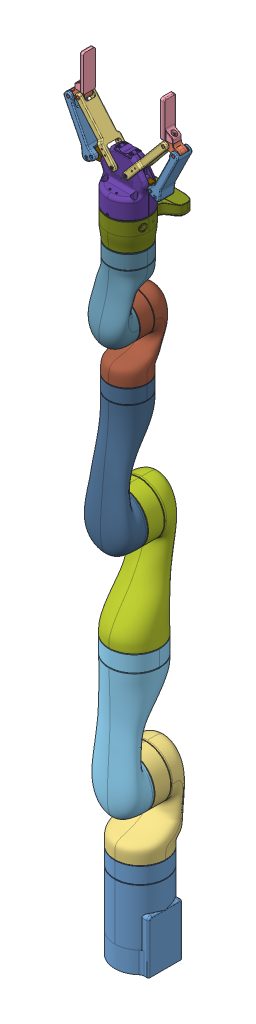
SolidWorks assembly KinovaGen3_7dof, configuration Default. Lengths in mm.
Overall size (315.52 1396.9 175).
44 component instances, 22 part files, 24 mates.
Components (placement in the parent):
- Link0.step-1: Link0.step [Default] at (18.2883 -95.8789 -1.2988) size (92.5 170.85 92.16)
- Link1.STEP-1: Link1.STEP [Default] at (23.0425 151.8211 81.9747) x (0 1 0) z (-0.992416 0 0.122925) size (174.42 105.54 103.77)
  - KR10643^GEN3 SIMPLIFIED Shoulder_Kinova Gen3 Modular Robotic Arm(2)_Kinova Gen3 Modular Robotic Arm.STEP-1: KR10643^GEN3 SIMPLIFIED Shoulder_Kinova Gen3 Modular Robotic Arm(2)_Kinova Gen3 Modular Robotic Arm.STEP [Default] at (34.35 77.8922 -4.8576) x (1 0 0) z (0 0.122925 0.992416) size (80 30.1 80)
  - GEN3 SIMPLIFIED SHOULDER_1^GEN3 SIMPLIFIED Shoulder_Kinova Gen3 Modular Robotic Arm(2)_Kinova Gen3 Modular Robotic Arm.STEP-1: GEN3 SIMPLIFIED SHOULDER_1^GEN3 SIMPLIFIED Shoulder_Kinova Gen3 Modular Robotic Arm(2)_Kinova Gen3 Modular Robotic Arm.STEP [Default] at (-91.65 83.2264 -5.5183) x (1 0 0) z (0 0.122925 0.992416) size (172.05 94.85 92.82)
  - KR10643^GEN3 SIMPLIFIED Shoulder_Kinova Gen3 Modular Robotic Arm(2)_Kinova Gen3 Modular Robotic Arm.STEP-2: KR10643^GEN3 SIMPLIFIED Shoulder_Kinova Gen3 Modular Robotic Arm(2)_Kinova Gen3 Modular Robotic Arm.STEP [Default] at (-94.025 83.2264 -5.5183) x (0 0.992416 -0.122925) z (0 -0.122925 -0.992416) size (80 30.1 80)
- LInk2.STEP-1: LInk2.STEP [Default] at (-176.0617 181.4169 81.0247) x (0.642788 0.760235 0.094166) z (0.766044 -0.637913 -0.079015) size (274.25 129.5 251.02)
  - KR10643_1^GEN3 SIMPLIFIED HalfArm1_Kinova Gen3 Modular Robotic Arm(2)_Kinova Gen3 Modular Robotic Arm.STEP-1: KR10643_1^GEN3 SIMPLIFIED HalfArm1_Kinova Gen3 Modular Robotic Arm(2)_Kinova Gen3 Modular Robotic Arm.STEP [Default] at (281.7393 -97.4259 17.2986) x (0.094166 0.992416 -0.079015) z (0.642788 0 0.766044) size (80 30.1 80)
  - GEN3 SIMPLIFIED HALF ARM 1^GEN3 SIMPLIFIED HalfArm1_Kinova Gen3 Modular Robotic Arm(2)_Kinova Gen3 Modular Robotic Arm.STEP-1: GEN3 SIMPLIFIED HALF ARM 1^GEN3 SIMPLIFIED HalfArm1_Kinova Gen3 Modular Robotic Arm(2)_Kinova Gen3 Modular Robotic Arm.STEP [Default] at (121.805 -71.5655 151.4994) x (0.760235 -0.122925 -0.637913) z (0.642788 0 0.766044) size (270.81 96.95 92.17)
  - KR10643_1^GEN3 SIMPLIFIED HalfArm1_Kinova Gen3 Modular Robotic Arm(2)_Kinova Gen3 Modular Robotic Arm.STEP-2: KR10643_1^GEN3 SIMPLIFIED HalfArm1_Kinova Gen3 Modular Robotic Arm(2)_Kinova Gen3 Modular Robotic Arm.STEP [Default] at (121.2047 -77.8922 152.0032) x (0.760235 -0.122925 -0.637913) z (0.642788 0 0.766044) size (80 30.1 80)
- Link3.STEP-1: Link3.STEP [Default] at (-39.2537 553.4933 127.2296) x (-0.34202 -0.932566 -0.115512) z (0.939693 -0.339426 -0.042043) size (279.6 127.43 176.9)
  - KR10643_2^GEN3 SIMPLIFIED HalfArm2_Kinova Gen3 Modular Robotic Arm(2)_Kinova Gen3 Modular Robotic Arm.STEP-1: KR10643_2^GEN3 SIMPLIFIED HalfArm2_Kinova Gen3 Modular Robotic Arm(2)_Kinova Gen3 Modular Robotic Arm.STEP [Default] at (-55.7569 116.9597 40.941) x (-0.917484 0.122818 -0.378337) z (0.380631 -0.005129 -0.924713) size (80 30.1 80)
  - GEN3 SIMPLIFIED HALF ARM 2^GEN3 SIMPLIFIED HalfArm2_Kinova Gen3 Modular Robotic Arm(2)_Kinova Gen3 Modular Robotic Arm.STEP-1: GEN3 SIMPLIFIED HALF ARM 2^GEN3 SIMPLIFIED HalfArm2_Kinova Gen3 Modular Robotic Arm(2)_Kinova Gen3 Modular Robotic Arm.STEP [Default] at (-55.0205 123.2864 41.2091) x (0.932566 -0.122925 0.339426) z (-0.34202 0 0.939693) size (254.01 96.94 92.16)
  - KR10643_2^GEN3 SIMPLIFIED HalfArm2_Kinova Gen3 Modular Robotic Arm(2)_Kinova Gen3 Modular Robotic Arm.STEP-2: KR10643_2^GEN3 SIMPLIFIED HalfArm2_Kinova Gen3 Modular Robotic Arm(2)_Kinova Gen3 Modular Robotic Arm.STEP [Default] at (141.1681 97.4259 112.6159) x (-0.34202 0 0.939693) z (-0.115512 -0.992416 -0.042043) size (80 30.1 80)
- Link4.STEP-1: Link4.STEP [Default] at (-236.8991 998.0236 80.0747) x (-0.838006 0.531634 -0.122925) z (-0.535697 -0.84441 0) size (229.54 111.76 274.7)
  - Kinova Gen3 Modular Robotic Arm(2)^Kinova Gen3 Modular Robotic Arm.STEP-1: Kinova Gen3 Modular Robotic Arm(2)^Kinova Gen3 Modular Robotic Arm.STEP [Default] at origin size (229.54 111.76 274.7)
    - GEN3 SIMPLIFIED Forearm^Kinova Gen3 Modular Robotic Arm(2)_Kinova Gen3 Modular Robotic Arm.STEP-1: GEN3 SIMPLIFIED Forearm^Kinova Gen3 Modular Robotic Arm(2)_Kinova Gen3 Modular Robotic Arm.STEP [Default] at (-400 -100 0) x (0 0 1) z (1 0 0) size (274.7 111.76 229.54)
      - KR12943^GEN3 SIMPLIFIED Forearm_Kinova Gen3 Modular Robotic Arm(2)_Kinova Gen3 Modular Robotic Arm.STEP-1: KR12943^GEN3 SIMPLIFIED Forearm_Kinova Gen3 Modular Robotic Arm(2)_Kinova Gen3 Modular Robotic Arm.STEP [Default] at (18.3538 -196.9081 95.7535) x (0 0.992416 -0.122925) z (-0.535697 -0.1038 -0.838006) size (61.5 32 61.5)
      - KR10643_3^GEN3 SIMPLIFIED Forearm_Kinova Gen3 Modular Robotic Arm(2)_Kinova Gen3 Modular Robotic Arm.STEP-1: KR10643_3^GEN3 SIMPLIFIED Forearm_Kinova Gen3 Modular Robotic Arm(2)_Kinova Gen3 Modular Robotic Arm.STEP [Default] at (194.35 -216.9597 -14.2687) x (-0.84441 0.065851 0.531634) z (-0.535697 -0.1038 -0.838006) size (80 30.1 80)
      - GEN3 SIMPLIFIED FOREARM_1^GEN3 SIMPLIFIED Forearm_Kinova Gen3 Modular Robotic Arm(2)_Kinova Gen3 Modular Robotic Arm.STEP-1: GEN3 SIMPLIFIED FOREARM_1^GEN3 SIMPLIFIED Forearm_Kinova Gen3 Modular Robotic Arm(2)_Kinova Gen3 Modular Robotic Arm.STEP [Default] at (194.35 -210.6331 -15.0524) x (-0.84441 0.065851 0.531634) z (-0.535697 -0.1038 -0.838006) size (266.9 85.28 92.08)
- Link5.STEP-2: Link5.STEP [Default] at (-236.8991 997.0735 80.0747) x (-0.838006 0.531634 -0.122925) z (-0.535697 -0.84441 0) size (143.15 103.97 154.47)
  - Kinova Gen3 Modular Robotic Arm.step.STEP-1: Kinova Gen3 Modular Robotic Arm.step.STEP [Default] at origin size (143.15 103.97 154.47)
    - GEN3 SIMPLIFIED Spherical Wrist1.step.STEP-1: GEN3 SIMPLIFIED Spherical Wrist1.step.STEP [Default] at (0 0 425) x (0 0 1) z (-1 0 0) size (154.47 103.97 143.15)
      - GEN3 SIMPLIFIED WRIST 1.step.STEP-1: GEN3 SIMPLIFIED WRIST 1.step.STEP [Default] at (-408.694 96.7484 302.9572) x (-0.84441 -0.065851 -0.531634) z (0.535697 -0.1038 -0.838006) size (138.51 88.25 70.01)
      - KR12943_1.step.STEP-1: KR12943_1.step.STEP [Default] at (-406.6462 96.9081 304.2465) x (0 -0.992416 0.122925) z (0.535697 -0.1038 -0.838006) size (61.5 32 61.5)
      - KR12943_1.step.STEP-2: KR12943_1.step.STEP [Default] at (-496.0904 89.7592 247.9546) x (-0.84441 -0.065851 -0.531634) z (0.535697 -0.1038 -0.838006) size (61.5 32 61.5)
- Link6.STEP-3: Link6.STEP [Default] at (514.8661 663.2059 79.1246) x (-0.999998 -0.001899 0) z (-0.001885 0.992414 0.122925) size (70.3 106.47 163.3)
  - KR12943_2^GEN3 SIMPLIFIED Spherical Wrist2_Kinova Gen3 Modular Robotic Arm(2)_Kinova Gen3 Modular Robotic Arm.STEP-1: KR12943_2^GEN3 SIMPLIFIED Spherical Wrist2_Kinova Gen3 Modular Robotic Arm(2)_Kinova Gen3 Modular Robotic Arm.STEP [Default] at (495.8893 -102.6063 353.0976) x (0 -0.992416 -0.122925) z (0.999998 -0.000233 0.001885) size (61.5 32 61.5)
  - GEN3 SIMPLIFIED WRIST 2^GEN3 SIMPLIFIED Spherical Wrist2_Kinova Gen3 Modular Robotic Arm(2)_Kinova Gen3 Modular Robotic Arm.STEP-1: GEN3 SIMPLIFIED WRIST 2^GEN3 SIMPLIFIED Spherical Wrist2_Kinova Gen3 Modular Robotic Arm(2)_Kinova Gen3 Modular Robotic Arm.STEP [Default] at (495.8939 -102.3082 350.691) x (0.001899 0.122925 -0.992414) z (0.999998 -0.000233 0.001885) size (153.49 88.25 70.01)
  - KR12943_2^GEN3 SIMPLIFIED Spherical Wrist2_Kinova Gen3 Modular Robotic Arm(2)_Kinova Gen3 Modular Robotic Arm.STEP-2: KR12943_2^GEN3 SIMPLIFIED Spherical Wrist2_Kinova Gen3 Modular Robotic Arm(2)_Kinova Gen3 Modular Robotic Arm.STEP [Default] at (496.0904 -89.7592 247.9546) x (0.001899 0.122925 -0.992414) z (0.999998 -0.000233 0.001885) size (61.5 32 61.5)
- Link7.STEP-2: Link7.STEP [Default] at (-453.2895 663.2083 -37.7223) x (-0.001885 -0.992414 0.122925) z (-0.999998 0.001899 0) size (77.51 122.73 92.29)
  - KR12943_3^GEN3 SIMPLIFIED Vision_Kinova Gen3 Modular Robotic Arm(2)_Kinova Gen3 Modular Robotic Arm.STEP-1: KR12943_3^GEN3 SIMPLIFIED Vision_Kinova Gen3 Modular Robotic Arm(2)_Kinova Gen3 Modular Robotic Arm.STEP [Default] at (-384.8549 106.5399 -470.8285) x (0.122925 0.992416 0) z (-0.001885 0.000233 -0.999998) size (61.5 32 61.5)
  - GEN3 SIMPLIFIED VISION with interface NO GRIPPER NO CAP^GEN3 SIMPLIFIED Vision_Kinova Gen3 Modular Robotic Arm(2)_Kinova Gen3 Modular Robotic Arm.STEP-1: GEN3 SIMPLIFIED VISION with interface NO GRIPPER NO CAP^GEN3 SIMPLIFIED Vision_Kinova Gen3 Modular Robotic Arm(2)_Kinova Gen3 Modular Robotic Arm.STEP [Default] at (-355.5787 102.9136 -470.8845) x (-0.001885 0.000233 -0.999998) z (-0.992414 0.122925 0.001899) size (92.17 115.98 61.93)
- Robotiq_2F-140.STEP-1: Robotiq_2F-140.STEP [Default] at (18.0008 1089.2541 -190.6327) size (211.89 213.35 75.05)
  - 2F-Body.STEP-1: 2F-Body.STEP [Default] at (0.2875 0.017 211.3339) size (89.61 93.41 75.05)
  - Finger1.STEP-1: Finger1.STEP [Default] at (-1.1166 -0.7424 211.3339) x (0.999678 -0.025395 0) z (0 0 1) size (33.04 20.16 9.4)
  - Finger1.STEP-2: Finger1.STEP [Default] at (2.1121 -0.9609 211.3339) x (-0.999458 -0.032929 0) z (0 0 -1) size (33.04 20.16 9.4)
  - Finger2.STEP-1: Finger2.STEP [Default] at (-1.1166 -0.7424 211.3339) x (0.999678 -0.025395 0) z (0 0 1) size (58 91.26 27.2)
  - Finger4.STEP-1: Finger4.STEP [Default] at (2.1976 1.6908 211.3339) size (29.9 28.02 27)
  - Finger3.STEP-1: Finger3.STEP [Default] at (-1.2763 -0.2857 211.2839) x (0.999678 -0.025395 0) z (0 0 1) size (78.86 86.37 35)
  - Fingertip.STEP-1: Fingertip.STEP [Default] at (2.1976 1.6908 211.3339) size (19.16 65.5 22)
  - Finger2.STEP-2: Finger2.STEP [Default] at (2.1121 -0.9609 211.1339) x (-0.999458 -0.032929 0) z (0 0 -1) size (58 91.26 27.2)
  - Finger4.STEP-2: Finger4.STEP [Default] at (-2.1976 2.1782 211.1339) x (-1 0 0) z (0 0 -1) size (29.9 28.02 27)
  - Finger3.STEP-2: Finger3.STEP [Default] at (-46.0759 40.3369 211.2839) x (0.138765 -0.990325 0) z (0 0 1) size (78.86 86.37 35)
  - Fingertip.STEP-2: Fingertip.STEP [Default] at (-2.1976 2.1782 211.1339) x (-1 0 0) z (0 0 -1) size (19.16 65.5 22)
Mates (geometry in assembly coordinates):
- Concentric1: concentric aligned: cylinder of Link0.step-1 through (18.2883 52.6211 -1.2988) axis (0 -1 0) radius 44; cylinder of Link1.STEP-1/GEN3 SIMPLIFIED SHOULDER_1^GEN3 SIMPLIFIED Shoulder_Kinova Gen3 Modular Robotic Arm(2)_Kinova Gen3 Modular Robotic Arm.STEP-1 through (18.2883 73.1711 -1.2988) axis (0 -1 0) radius 43.98
- Coincident1: coincident anti-aligned: plane of Link0.step-1 through (18.2883 73.1711 -47.2988) normal (0 1 0); plane of Link1.STEP-1/GEN3 SIMPLIFIED SHOULDER_1^GEN3 SIMPLIFIED Shoulder_Kinova Gen3 Modular Robotic Arm(2)_Kinova Gen3 Modular Robotic Arm.STEP-1 through (18.2883 73.1711 -1.2988) normal (0 -1 0)
- Concentric2: concentric anti-aligned: cylinder of Link1.STEP-1/GEN3 SIMPLIFIED SHOULDER_1^GEN3 SIMPLIFIED Shoulder_Kinova Gen3 Modular Robotic Arm(2)_Kinova Gen3 Modular Robotic Arm.STEP-1 through (18.2883 186.1711 18.5012) axis (0 0 -1) radius 45; cylinder of LInk2.STEP-1/GEN3 SIMPLIFIED HALF ARM 1^GEN3 SIMPLIFIED HalfArm1_Kinova Gen3 Modular Robotic Arm(2)_Kinova Gen3 Modular Robotic Arm.STEP-1 through (18.2883 186.1711 5.5012) axis (0 0 1) radius 43.98
- Coincident2: coincident: point of Link1.STEP-1/GEN3 SIMPLIFIED SHOULDER_1^GEN3 SIMPLIFIED Shoulder_Kinova Gen3 Modular Robotic Arm(2)_Kinova Gen3 Modular Robotic Arm.STEP-1; plane of LInk2.STEP-1/GEN3 SIMPLIFIED HALF ARM 1^GEN3 SIMPLIFIED HalfArm1_Kinova Gen3 Modular Robotic Arm(2)_Kinova Gen3 Modular Robotic Arm.STEP-1 through (18.2883 140.1911 18.5012) normal (0 0 -1)
- Concentric3: concentric anti-aligned: cylinder of LInk2.STEP-1/GEN3 SIMPLIFIED HALF ARM 1^GEN3 SIMPLIFIED HalfArm1_Kinova Gen3 Modular Robotic Arm(2)_Kinova Gen3 Modular Robotic Arm.STEP-1 through (18.2883 410.9711 9.5012) axis (0 -1 0) radius 45; cylinder of Link3.STEP-1/GEN3 SIMPLIFIED HALF ARM 2^GEN3 SIMPLIFIED HalfArm2_Kinova Gen3 Modular Robotic Arm(2)_Kinova Gen3 Modular Robotic Arm.STEP-1 through (18.2883 397.9711 9.5012) axis (0 1 0) radius 43.98
- Coincident3: coincident: point of LInk2.STEP-1/GEN3 SIMPLIFIED HALF ARM 1^GEN3 SIMPLIFIED HalfArm1_Kinova Gen3 Modular Robotic Arm(2)_Kinova Gen3 Modular Robotic Arm.STEP-1; plane of Link3.STEP-1/GEN3 SIMPLIFIED HALF ARM 2^GEN3 SIMPLIFIED HalfArm2_Kinova Gen3 Modular Robotic Arm(2)_Kinova Gen3 Modular Robotic Arm.STEP-1 through (18.2883 410.9711 55.4812) normal (0 -1 0)
- Concentric4: concentric anti-aligned: cylinder of Link3.STEP-1/GEN3 SIMPLIFIED HALF ARM 2^GEN3 SIMPLIFIED HalfArm2_Kinova Gen3 Modular Robotic Arm(2)_Kinova Gen3 Modular Robotic Arm.STEP-1 through (18.2883 605.9711 30.3012) axis (0 0 -1) radius 45; cylinder of Link4.STEP-1/Kinova Gen3 Modular Robotic Arm(2)^Kinova Gen3 Modular Robotic Arm.STEP-1/GEN3 SIMPLIFIED Forearm^Kinova Gen3 Modular Robotic Arm(2)_Kinova Gen3 Modular Robotic Arm.STEP-1/GEN3 SIMPLIFIED FOREARM_1^GEN3 SIMPLIFIED Forearm_Kinova Gen3 Modular Robotic Arm(2)_Kinova Gen3 Modular Robotic Arm.STEP-1 through (18.2883 605.9711 17.3012) axis (0 0 1) radius 43.98
- Coincident4: coincident: point of Link3.STEP-1/GEN3 SIMPLIFIED HALF ARM 2^GEN3 SIMPLIFIED HalfArm2_Kinova Gen3 Modular Robotic Arm(2)_Kinova Gen3 Modular Robotic Arm.STEP-1; plane of Link4.STEP-1/Kinova Gen3 Modular Robotic Arm(2)^Kinova Gen3 Modular Robotic Arm.STEP-1/GEN3 SIMPLIFIED Forearm^Kinova Gen3 Modular Robotic Arm(2)_Kinova Gen3 Modular Robotic Arm.STEP-1/GEN3 SIMPLIFIED FOREARM_1^GEN3 SIMPLIFIED Forearm_Kinova Gen3 Modular Robotic Arm(2)_Kinova Gen3 Modular Robotic Arm.STEP-1 through (18.2883 559.9911 30.3012) normal (0 0 -1)
- Concentric6: concentric anti-aligned: cylinder of Link4.STEP-1/Kinova Gen3 Modular Robotic Arm(2)^Kinova Gen3 Modular Robotic Arm.STEP-1/GEN3 SIMPLIFIED Forearm^Kinova Gen3 Modular Robotic Arm(2)_Kinova Gen3 Modular Robotic Arm.STEP-1/GEN3 SIMPLIFIED FOREARM_1^GEN3 SIMPLIFIED Forearm_Kinova Gen3 Modular Robotic Arm(2)_Kinova Gen3 Modular Robotic Arm.STEP-1 through (18.2883 826.8711 21.3012) axis (0 -1 0) radius 35; cylinder of Link5.STEP-2/Kinova Gen3 Modular Robotic Arm.step.STEP-1/GEN3 SIMPLIFIED Spherical Wrist1.step.STEP-1/GEN3 SIMPLIFIED WRIST 1.step.STEP-1 through (18.2883 815.946 21.3012) axis (0 1 0) radius 33.23
- Coincident5: coincident: point of Link4.STEP-1/Kinova Gen3 Modular Robotic Arm(2)^Kinova Gen3 Modular Robotic Arm.STEP-1/GEN3 SIMPLIFIED Forearm^Kinova Gen3 Modular Robotic Arm(2)_Kinova Gen3 Modular Robotic Arm.STEP-1/GEN3 SIMPLIFIED FOREARM_1^GEN3 SIMPLIFIED Forearm_Kinova Gen3 Modular Robotic Arm(2)_Kinova Gen3 Modular Robotic Arm.STEP-1; plane of Link5.STEP-2/Kinova Gen3 Modular Robotic Arm.step.STEP-1/GEN3 SIMPLIFIED Spherical Wrist1.step.STEP-1/GEN3 SIMPLIFIED WRIST 1.step.STEP-1 through (-16.6917 826.8711 21.3012) normal (0 -1 0)
- Concentric8: concentric anti-aligned: cylinder of Link5.STEP-2/Kinova Gen3 Modular Robotic Arm.step.STEP-1/GEN3 SIMPLIFIED Spherical Wrist1.step.STEP-1/GEN3 SIMPLIFIED WRIST 1.step.STEP-1 through (18.2883 919.3711 33.9512) axis (0 0 -1) radius 34; cylinder of Link6.STEP-3/GEN3 SIMPLIFIED WRIST 2^GEN3 SIMPLIFIED Spherical Wrist2_Kinova Gen3 Modular Robotic Arm(2)_Kinova Gen3 Modular Robotic Arm.STEP-1 through (18.2883 919.3711 23.0261) axis (0 0 1) radius 33.23
- Coincident6: coincident: point of Link5.STEP-2/Kinova Gen3 Modular Robotic Arm.step.STEP-1/GEN3 SIMPLIFIED Spherical Wrist1.step.STEP-1/GEN3 SIMPLIFIED WRIST 1.step.STEP-1; plane of Link6.STEP-3/GEN3 SIMPLIFIED WRIST 2^GEN3 SIMPLIFIED Spherical Wrist2_Kinova Gen3 Modular Robotic Arm(2)_Kinova Gen3 Modular Robotic Arm.STEP-1 through (-16.6917 919.3711 33.9512) normal (0 0 -1)
- Concentric9: concentric aligned: cylinder of Link6.STEP-3/GEN3 SIMPLIFIED WRIST 2^GEN3 SIMPLIFIED Spherical Wrist2_Kinova Gen3 Modular Robotic Arm(2)_Kinova Gen3 Modular Robotic Arm.STEP-1 through (18.2883 1037.7711 20.7012) axis (0 -1 0) radius 34; cylinder of Link7.STEP-2/GEN3 SIMPLIFIED VISION with interface NO GRIPPER NO CAP^GEN3 SIMPLIFIED Vision_Kinova Gen3 Modular Robotic Arm(2)_Kinova Gen3 Modular Robotic Arm.STEP-1 through (18.2883 1027.8461 20.7012) axis (0 -1 0) radius 33.23
- Coincident7: coincident: point of Link6.STEP-3/GEN3 SIMPLIFIED WRIST 2^GEN3 SIMPLIFIED Spherical Wrist2_Kinova Gen3 Modular Robotic Arm(2)_Kinova Gen3 Modular Robotic Arm.STEP-1; plane of Link7.STEP-2/GEN3 SIMPLIFIED VISION with interface NO GRIPPER NO CAP^GEN3 SIMPLIFIED Vision_Kinova Gen3 Modular Robotic Arm(2)_Kinova Gen3 Modular Robotic Arm.STEP-1 through (18.2883 1037.7711 -12.5288) normal (0 -1 0)
- 1轴临时固定: parallel aligned: plane of LInk2.STEP-1/KR10643_1^GEN3 SIMPLIFIED HalfArm1_Kinova Gen3 Modular Robotic Arm(2)_Kinova Gen3 Modular Robotic Arm.STEP-2 through (18.2883 186.1711 33.2262) normal (0 0 1)
- 2轴临时固定: parallel aligned: plane of Link3.STEP-1/KR10643_2^GEN3 SIMPLIFIED HalfArm2_Kinova Gen3 Modular Robotic Arm(2)_Kinova Gen3 Modular Robotic Arm.STEP-2 through (18.2883 425.6961 9.5012) normal (0 1 0)
- 3轴临时固定: parallel aligned: plane of Link4.STEP-1/Kinova Gen3 Modular Robotic Arm(2)^Kinova Gen3 Modular Robotic Arm.STEP-1/GEN3 SIMPLIFIED Forearm^Kinova Gen3 Modular Robotic Arm(2)_Kinova Gen3 Modular Robotic Arm.STEP-1/KR10643_3^GEN3 SIMPLIFIED Forearm_Kinova Gen3 Modular Robotic Arm(2)_Kinova Gen3 Modular Robotic Arm.STEP-1 through (18.2883 605.9711 45.0262) normal (0 0 1)
- 4轴临时固定: parallel aligned: plane of Link5.STEP-2/Kinova Gen3 Modular Robotic Arm.step.STEP-1/GEN3 SIMPLIFIED Spherical Wrist1.step.STEP-1/KR12943_1.step.STEP-1 through (18.2883 845.446 21.3012) normal (0 1 0)
- Parallel8: parallel aligned: plane of Link6.STEP-3/KR12943_2^GEN3 SIMPLIFIED Spherical Wrist2_Kinova Gen3 Modular Robotic Arm(2)_Kinova Gen3 Modular Robotic Arm.STEP-2 through (18.2883 919.3711 52.5261) normal (0 0 1)
- Parallel9: parallel aligned: plane of Link7.STEP-2/KR12943_3^GEN3 SIMPLIFIED Vision_Kinova Gen3 Modular Robotic Arm(2)_Kinova Gen3 Modular Robotic Arm.STEP-1 through (18.2883 1057.3461 20.7012) normal (0 1 0)
- Parallel10: parallel aligned: plane of Link7.STEP-2/GEN3 SIMPLIFIED VISION with interface NO GRIPPER NO CAP^GEN3 SIMPLIFIED Vision_Kinova Gen3 Modular Robotic Arm(2)_Kinova Gen3 Modular Robotic Arm.STEP-1 through (9.9308 1072.0461 -3.2988) normal (0 0 1)
- Concentric10: concentric aligned: cylinder of Link7.STEP-2/GEN3 SIMPLIFIED VISION with interface NO GRIPPER NO CAP^GEN3 SIMPLIFIED Vision_Kinova Gen3 Modular Robotic Arm(2)_Kinova Gen3 Modular Robotic Arm.STEP-1 through (18.2883 1027.8461 20.7012) axis (0 -1 0) radius 37.5; cylinder of Robotiq_2F-140.STEP-1/2F-Body.STEP-1 through (18.2883 1161.2925 20.7012) axis (0 -1 0) radius 37.5
- Concentric11: concentric aligned: cylinder of Link7.STEP-2/GEN3 SIMPLIFIED VISION with interface NO GRIPPER NO CAP^GEN3 SIMPLIFIED Vision_Kinova Gen3 Modular Robotic Arm(2)_Kinova Gen3 Modular Robotic Arm.STEP-1 through (-8.7117 1086.8711 36.7012) axis (0 1 0) radius 2.1; cylinder of Robotiq_2F-140.STEP-1/2F-Body.STEP-1 through (-8.7117 1125.5711 36.7012) axis (0 1 0) radius 2.75
- Coincident9: coincident aligned: plane of Link7.STEP-2/GEN3 SIMPLIFIED VISION with interface NO GRIPPER NO CAP^GEN3 SIMPLIFIED Vision_Kinova Gen3 Modular Robotic Arm(2)_Kinova Gen3 Modular Robotic Arm.STEP-1 through (18.2883 1089.7711 -16.7988) normal (0 1 0); circle of Robotiq_2F-140.STEP-1/2F-Body.STEP-1
